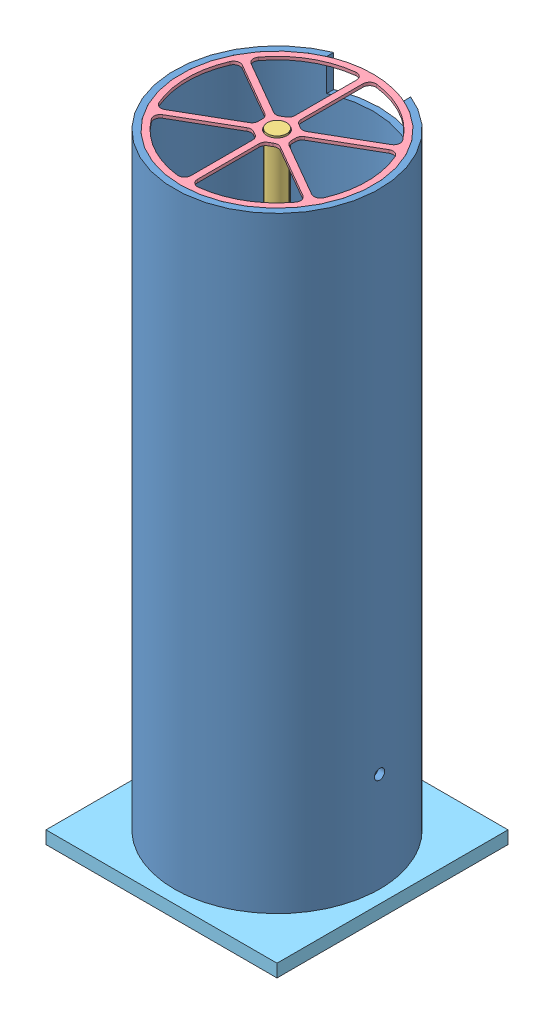
SolidWorks assembly Reactor, configuration Default. Lengths in mm.
Overall size (130.11 307.02 130.11).
8 component instances, 5 part files, 11 mates.
Components (placement in the parent):
- PC-Tube-1: PC-Tube [Default] at (-19.9711 -139.5381 2.8788) size (101.6 301.62 101.6)
- Auger-1: Auger [Default] at (-23.5409 -107.8741 23.7559) x (0.012559 0 0.999921) z (0 1 0) size (76.48 66.77 304.8)
  - 1-flute auger-1: 1-flute auger [Default] at (-20.8306 3.8317 -30.0765) size (67.09 57.28 78.42)
  - 1-flute auger-2: 1-flute auger [Default] at (-20.8306 3.8317 -30.0765) x (-1 0 0) z (0 0 1) size (67.09 57.28 78.42)
  - Auger spindle-1: Auger spindle [Default] at (-20.8306 3.8317 -34.204) x (0 1 0) z (1 0 0) size (9.53 304.8 9.53)
- Ring-1: Ring [Default] at (-19.9711 -37.9381 2.8788) x (0.5 0 0.866025) z (-0.866025 0 0.5) size (95.25 1.52 95.25)
- Ring-2: Ring [Default] at (-19.9711 160.5629 2.8788) size (95.25 1.52 95.25)
- base-1: base [Default] at (-19.9711 -144.3006 2.8788) size (114.3 6.35 114.3)
Mates (geometry in assembly coordinates):
- Concentric1: concentric anti-aligned: cylinder of PC-Tube-1 through (-19.9711 162.0869 2.8788) axis (0 -1 0) radius 50.8; cylinder of Auger-1/Auger spindle-1 through (-19.9711 162.7219 2.8788) axis (0 1 0) radius 4.7625
- Distance1: distance = 1.5875 mm aligned: plane of Auger-1/1-flute auger-2 through (-19.9711 -137.9506 2.8788) normal (0 -1 0); plane of PC-Tube-1 through (-19.9711 -139.5381 2.8788) normal (0 -1 0)
- Concentric2: concentric aligned: cylinder of PC-Tube-1 through (-19.9711 162.0869 2.8788) axis (0 -1 0) radius 50.8; cylinder of Ring-1 through (-19.9711 -36.4141 2.8788) axis (0 -1 0) radius 5.08
- Distance2: distance = 101.6 mm aligned: plane of Ring-1 through (-19.9711 -37.9381 2.8788) normal (0 -1 0); plane of PC-Tube-1 through (-19.9711 -139.5381 2.8788) normal (0 -1 0)
- Concentric3: concentric aligned: cylinder of PC-Tube-1 through (-19.9711 162.0869 2.8788) axis (0 -1 0) radius 50.8; cylinder of Ring-2 through (-19.9711 162.0869 2.8788) axis (0 -1 0) radius 5.08
- Coincident3: coincident aligned: plane of PC-Tube-1 through (-19.9711 162.0869 2.8788) normal (0 1 0); plane of Ring-2 through (-19.9711 162.0869 2.8788) normal (0 1 0)
- Concentric4: concentric aligned: cylinder of Auger-1/Auger spindle-1 through (-19.9711 162.7219 2.8788) axis (0 1 0) radius 1.5875; cylinder of base-1 through (-19.9711 -141.1256 2.8788) axis (0 1 0) radius 1.651
- Coincident4: coincident anti-aligned: plane of PC-Tube-1 through (-19.9711 -139.5381 2.8788) normal (0 -1 0); plane of base-1 through (-19.9711 -139.5381 2.8788) normal (0 1 0)
- Parallel1: parallel anti-aligned: plane of PC-Tube-1 through (-19.9711 -139.5381 2.8788) normal (1 0 0); plane of base-1 through (-77.1211 -137.9506 60.0288) normal (-1 0 0)
- Coincident6: coincident aligned: plane of Ring-1 through (-21.5586 -36.4141 -7.5117) normal (-1 0 0); plane of Ring-2 through (-21.5586 162.0869 -7.5117) normal (-1 0 0)
- Parallel2: parallel anti-aligned: plane of PC-Tube-1 through (-19.9711 -139.5381 2.8788) normal (1 0 0); plane of Ring-2 through (-21.5586 162.0869 -7.5117) normal (-1 0 0)
